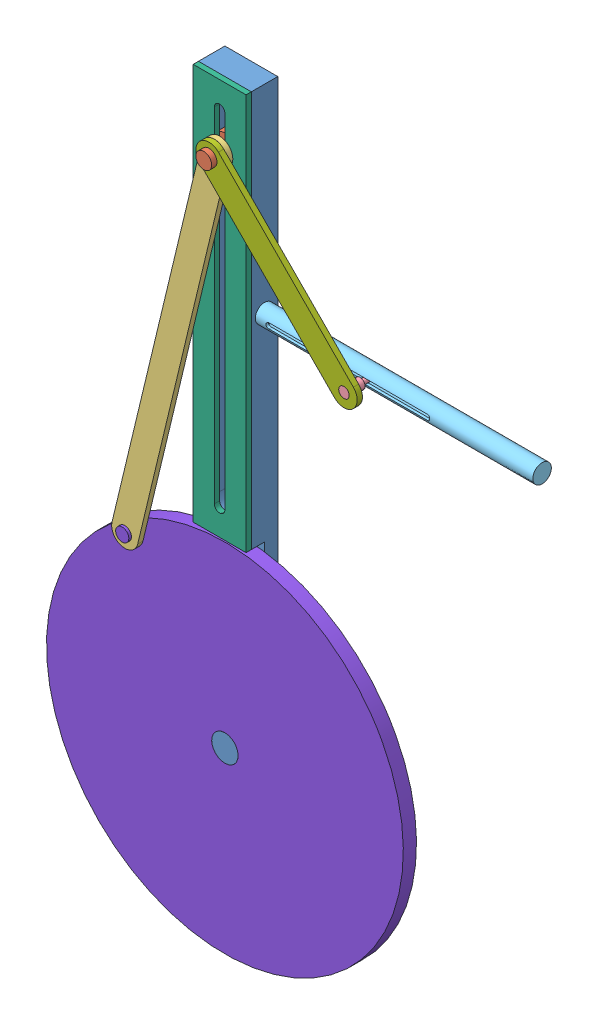
SolidWorks assembly Ensamblaje 3 Pieza 3 Tarea 2, configuration Predeterminado. Lengths in mm.
Overall size (207.78 312.78 18).
8 component instances, 8 part files, 17 mates.
Components (placement in the parent):
- T02 EJER03 Base-2-1: T02 EJER03 Base-2 [Default] at origin size (20 230 10)
- T02 EJER03 Cylinder Connector-1: T02 EJER03 Cylinder Connector [Default] at (0 -23.5158 0) x (-0.835778 0.549067 0) z (0.549067 0.835778 0) size (10 13 10)
- T02 EJER03 Large Link-1: T02 EJER03 Large Link [Default] at (-16.9248 -94.0126 7) x (0.97237 -0.233445 0) z (0 0 1) size (10 155 2)
- T02 EJER03 Piston-1: T02 EJER03 Piston [Default] at (51.0453 -75 5) size (42 5 13.5)
- T02 EJER03 Piston Cylinder-1: T02 EJER03 Piston Cylinder [Default] at (50 -75 0) size (107 7 7)
- T02 EJER03 Rail Lid-1: T02 EJER03 Rail Lid [Default] at (0 -75 7) x (1 0 0) z (0 1 0) size (20 7 150)
- T02 EJER03 Small Link-1: T02 EJER03 Small Link [Default] at (0 -23.5158 9) x (0.710127 0.704073 0) z (0 0 1) size (10 82.5 2)
- T02 EJER03 Wheel-1: T02 EJER03 Wheel [Default] at (0 -220 2.5) x (0.853701 0.520763 0) z (0 0 1) size (135 135 10)
Mates (geometry in assembly coordinates):
- Coincidente9: coincident aligned: plane of T02 EJER03 Base-2-1 through (0 -220 5) normal (0 0 1); plane of T02 EJER03 Wheel-1 through (0 -220 5) normal (0 0 1)
- Concéntrica5: concentric aligned: cylinder of T02 EJER03 Base-2-1 through (0 -220 5) axis (0 0 -1) radius 5; cylinder of T02 EJER03 Wheel-1 through (0 -220 5) axis (0 0 -1) radius 5
- Coincidente10: coincident anti-aligned: circle of T02 EJER03 Base-2-1; circle of T02 EJER03 Rail Lid-1
- Coincidente12: coincident anti-aligned: circle of T02 EJER03 Base-2-1; circle of T02 EJER03 Rail Lid-1
- Coincidente13: coincident anti-aligned: plane of T02 EJER03 Base-2-1 through (0 -140 0) normal (0 0 1); plane of T02 EJER03 Cylinder Connector-1 through (0 -30.2267 0) normal (0 0 -1)
- Ancho1: width: plane of T02 EJER03 Rail Lid-1 through (2 -10 7) normal (-1 0 0); plane of T02 EJER03 Cylinder Connector-1 through (-2 -10 7) normal (1 0 0); cylinder of T02 EJER03 Rail Lid-1 through (0 -30.2267 11) axis (0 0 -1) radius 2
- Coincidente14: coincident anti-aligned: plane of T02 EJER03 Large Link-1 through (-40.7711 -169.3767 7) normal (0 0 -1); plane of T02 EJER03 Rail Lid-1 through (0 -75 7) normal (0 0 1)
- Concéntrica6: concentric aligned: line of T02 EJER03 Large Link-1 through (-40.7711 -169.3767 9) axis (0 0 -1); axis of T02 EJER03 Wheel-1 through (-40.7711 -169.3767 9) axis (0 0 -1)
- Concéntrica7: concentric aligned: cylinder of T02 EJER03 Cylinder Connector-1 through (0 -30.2267 11) axis (0 0 -1) radius 2; cylinder of T02 EJER03 Large Link-1 through (0 -30.2267 9) axis (0 0 -1) radius 2
- Coincidente15: coincident anti-aligned: plane of T02 EJER03 Large Link-1 through (-40.7711 -169.3767 9) normal (0 0 1); plane of T02 EJER03 Small Link-1 through (57.0228 -75 9) normal (0 0 -1)
- Concéntrica8: concentric aligned: cylinder of T02 EJER03 Cylinder Connector-1 through (0 -30.2267 11) axis (0 0 -1) radius 2; cylinder of T02 EJER03 Small Link-1 through (0 -30.2267 11) axis (0 0 -1) radius 2
- Coincidente16: coincident anti-aligned: plane of T02 EJER03 Base-2-1 through (8 -75 0) normal (1 0 0); plane of T02 EJER03 Piston Cylinder-1 through (8 -75 0) normal (-1 0 0)
- Coincidente17: coincident aligned: circle of T02 EJER03 Base-2-1; circle of T02 EJER03 Piston Cylinder-1
- Concéntrica9: concentric anti-aligned: cylinder of T02 EJER03 Piston-1 through (97.0228 -75 0) axis (-1 0 0) radius 1; cylinder of T02 EJER03 Piston Cylinder-1 through (2.9289 -75 0) axis (1 0 0) radius 2.5
- Coincidente18: coincident aligned: line of T02 EJER03 Piston-1 through (57.0228 -75 11) axis (0 0 -1); line of T02 EJER03 Small Link-1 through (57.0228 -75 11) axis (0 0 -1)
- Ancho2: width: plane of T02 EJER03 Piston Cylinder-1 through (15 -76 3.5) normal (0 1 0); plane of T02 EJER03 Piston-1 through (15 -74 3.5) normal (0 -1 0); cylinder of T02 EJER03 Piston Cylinder-1 through (57.0228 -75 5) axis (0 0 -1) radius 1
- Ángulo3: planar angle = 0.235619 rad aligned: line of T02 EJER03 Large Link-1 through (-28.9877 -165.6766 9) axis (0.233445 0.97237 0); line of T02 EJER03 Rail Lid-1 through (-10 -150 7) axis (0 1 0)
